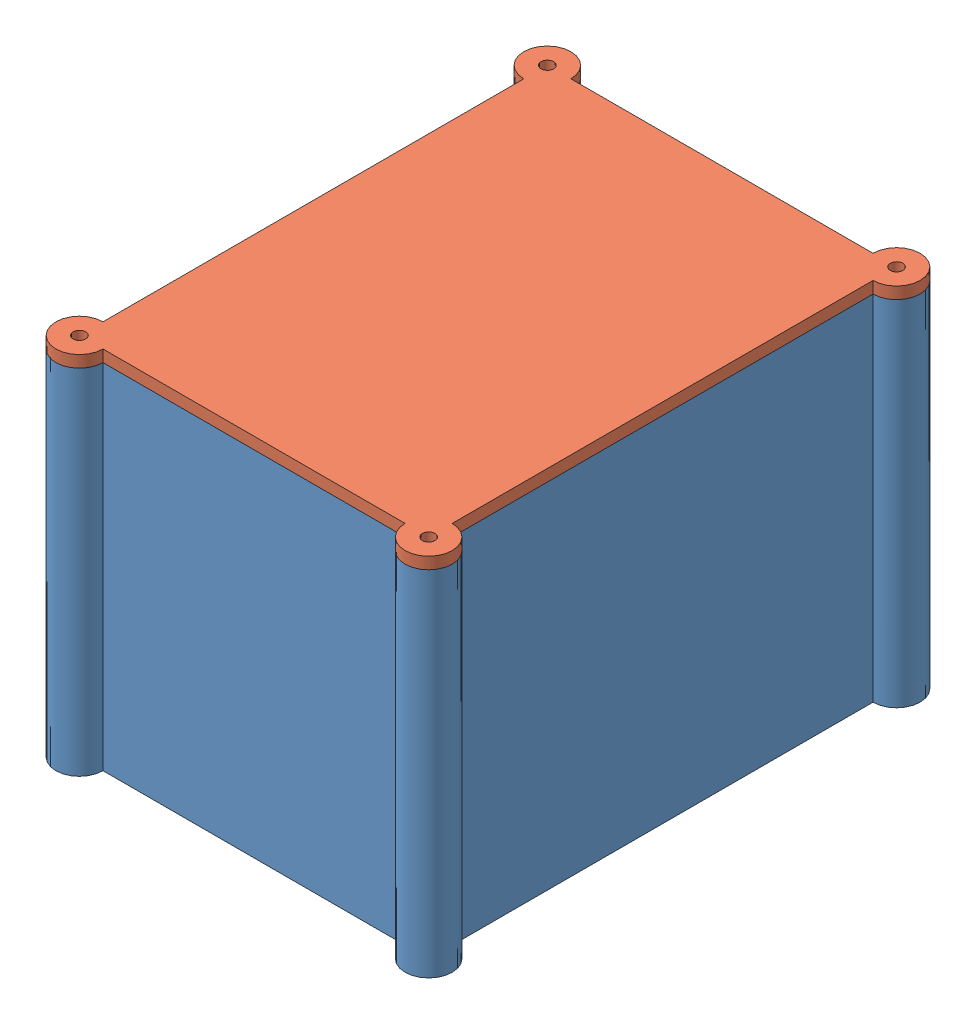
SolidWorks assembly Assem123, configuration Default. Lengths in mm.
Overall size (100.92 93 131.14).
2 component instances, 2 part files, 7 mates.
Components (placement in the parent):
- top 1final-1: top 1final [Default] at (-27.3225 -89.4029 -30.9269) x (1 0 0) z (0 0 -1) size (100.92 90 131.14)
- Part2^Assem123-1: Part2^Assem123 [Default] at (-27.3225 -2.4029 -30.9269) x (-1 0 0) z (0 1 0) size (100.92 131.14 3)
Mates (geometry in assembly coordinates):
- Coincident1: coincident: plane of ? through (7.8595 10.6562 47.1321) normal (0 0 1); plane of top 1final-1 through (-38.5583 7.6562 47.1321) normal (0 0 1)
- Coincident2: coincident: plane of ? through (7.8595 7.6562 -10.3679) normal (0 -1 0); plane of top 1final-1 through (5.9006 7.6562 -12.4389) normal (0 1 0)
- Coincident3: coincident: plane of ? through (50.3595 10.6562 -10.3679) normal (1 0 0); plane of top 1final-1 through (50.3595 7.6562 -72.0098) normal (1 0 0)
- InPlace1: in place: plane of ? through (5.9006 7.6562 -12.4389) normal (0 1 0); plane of ? through (0 7.6562 0) normal (0 1 0); moOrthogonalPlaneRef_w of ? through (5.9006 7.6562 -12.4389) normal (0 1 0); plane of ? through (0 7.6562 0) normal (0 0 -1); plane of ? through (5.9006 7.6562 -12.4389) normal (0 1 0); plane of ? through (0 7.6562 0) normal (1 0 0); plane of top 1final-1 through (-27.3225 -2.4029 -30.9269) normal (0 1 0); unknown of Part2^Assem123-1
- Coincident4: coincident: plane of top 1final-1; plane of Part2^Assem123-1
- Coincident5: coincident: moOrthogonalPlaneRef_w of top 1final-1 through (-27.3225 -2.4029 -30.9269) normal (0 0 1); plane of Part2^Assem123-1 through (-27.3225 -2.4029 -30.9269) normal (0 0 1)
- Coincident6: coincident: moOrthogonalPlaneRef_w of top 1final-1 through (-27.3225 -2.4029 -30.9269) normal (1 0 0); plane of Part2^Assem123-1 through (-27.3225 -2.4029 -30.9269) normal (-1 0 0)
